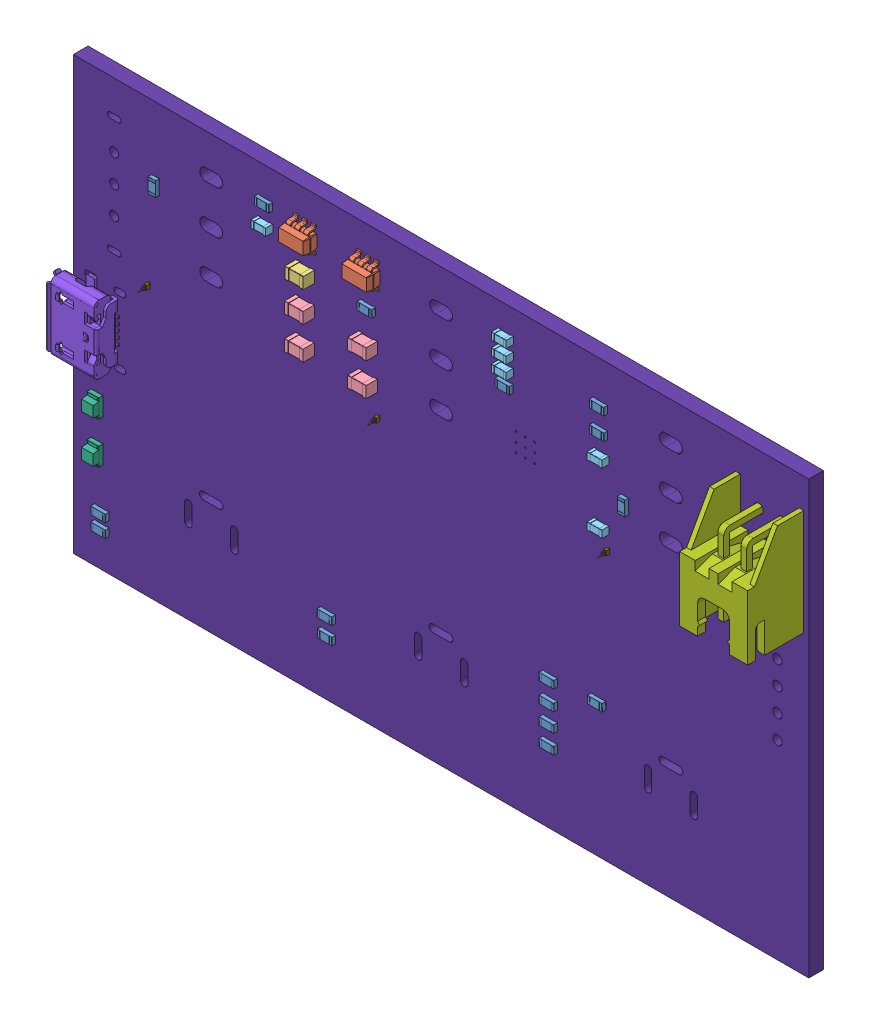
SolidWorks assembly ledTruck_PCB.step, configuration Default. Lengths in mm.
Overall size (80.38 47 12.68).
99 component instances, 19 part files, 0 mates.
Components (placement in the parent):
- ledTruck.step-1: ledTruck.step [Default] at origin size (80.38 47 12.68)
  - R_0603_1608Metric.step-1: R_0603_1608Metric.step [Default] at (162.2298 -104.8258 1.65) size (1.6 0.8 0.45)
    - SOLID.step-1: SOLID.step [Default] at origin size (1.6 0.8 0.45)
  - SOT-23-5.step-1: SOT-23-5.step [Default] at (130.302 -76.708 1.65) x (0 -1 0) z (0 0 1) size (2.8 2.9 1.55)
    - SOLID-0.step-1: SOLID-0.step [Default] at origin size (2.8 2.9 1.55)
  - SOT-23-5.step-2: SOT-23-5.step [Default] at (137.16 -76.708 1.65) x (0 -1 0) z (0 0 1) size (2.8 2.9 1.55)
    - SOLID-0.step-1: SOLID-0.step [Default] at origin size (2.8 2.9 1.55)
  - R_0603_1608Metric.step-2: R_0603_1608Metric.step [Default] at (162.433 -79.248 1.65) size (1.6 0.8 0.45)
    - SOLID.step-1: SOLID.step [Default] at origin size (1.6 0.8 0.45)
  - R_0603_1608Metric.step-3: R_0603_1608Metric.step [Default] at (162.433 -76.835 1.65) x (-1 0 0) z (0 0 1) size (1.6 0.8 0.45)
    - SOLID.step-1: SOLID.step [Default] at origin size (1.6 0.8 0.45)
  - R_0603_1608Metric.step-4: R_0603_1608Metric.step [Default] at (108.1929 -114.012 1.65) size (1.6 0.8 0.45)
    - SOLID.step-1: SOLID.step [Default] at origin size (1.6 0.8 0.45)
  - R_0603_1608Metric.step-5: R_0603_1608Metric.step [Default] at (108.1929 -115.512 1.65) size (1.6 0.8 0.45)
    - SOLID.step-1: SOLID.step [Default] at origin size (1.6 0.8 0.45)
  - R_0603_1608Metric.step-6: R_0603_1608Metric.step [Default] at (152.146 -80.01 1.65) size (1.6 0.8 0.45)
    - SOLID.step-1: SOLID.step [Default] at origin size (1.6 0.8 0.45)
  - R_0603_1608Metric.step-7: R_0603_1608Metric.step [Default] at (165.1 -84.836 1.65) x (0 1 0) z (0 0 1) size (1.6 0.8 0.45)
    - SOLID.step-1: SOLID.step [Default] at origin size (1.6 0.8 0.45)
  - R_0603_1608Metric.step-8: R_0603_1608Metric.step [Default] at (137.16 -80.264 1.65) x (-1 0 0) z (0 0 1) size (1.6 0.8 0.45)
    - SOLID.step-1: SOLID.step [Default] at origin size (1.6 0.8 0.45)
  - R_0603_1608Metric.step-9: R_0603_1608Metric.step [Default] at (156.972 -111.506 1.65) x (-1 0 0) z (0 0 1) size (1.6 0.8 0.45)
    - SOLID.step-1: SOLID.step [Default] at origin size (1.6 0.8 0.45)
  - R_0603_1608Metric.step-10: R_0603_1608Metric.step [Default] at (156.972 -107.442 1.65) size (1.6 0.8 0.45)
    - SOLID.step-1: SOLID.step [Default] at origin size (1.6 0.8 0.45)
  - R_0603_1608Metric.step-11: R_0603_1608Metric.step [Default] at (132.842 -113.284 1.65) size (1.6 0.8 0.45)
    - SOLID.step-1: SOLID.step [Default] at origin size (1.6 0.8 0.45)
  - R_0603_1608Metric.step-12: R_0603_1608Metric.step [Default] at (156.972 -109.474 1.65) x (-1 0 0) z (0 0 1) size (1.6 0.8 0.45)
    - SOLID.step-1: SOLID.step [Default] at origin size (1.6 0.8 0.45)
  - R_0603_1608Metric.step-13: R_0603_1608Metric.step [Default] at (156.972 -105.283 1.65) x (-1 0 0) z (0 0 1) size (1.6 0.8 0.45)
    - SOLID.step-1: SOLID.step [Default] at origin size (1.6 0.8 0.45)
  - R_0603_1608Metric.step-14: R_0603_1608Metric.step [Default] at (132.828 -111.379 1.65) size (1.6 0.8 0.45)
    - SOLID.step-1: SOLID.step [Default] at origin size (1.6 0.8 0.45)
  - L_0805_2012Metric.step-1: L_0805_2012Metric.step [Default] at (130.336 -80.264 1.65) x (-1 0 0) z (0 0 1) size (2 1.25 1.25)
    - SOLID-1.step-1: SOLID-1.step [Default] at origin size (2 1.25 1.25)
  - C_0805_2012Metric.step-1: C_0805_2012Metric.step [Default] at (130.302 -87.122 1.65) size (2 1.25 1.25)
    - SOLID-2.step-1: SOLID-2.step [Default] at origin size (2 1.25 1.25)
  - C_0603_1608Metric.step-1: C_0603_1608Metric.step [Default] at (152.146 -78.486 1.65) x (-1 0 0) z (0 0 1) size (1.6 0.8 0.8)
    - SOLID-3.step-1: SOLID-3.step [Default] at origin size (1.6 0.8 0.8)
  - C_0805_2012Metric.step-2: C_0805_2012Metric.step [Default] at (137.16 -83.566 1.65) size (2 1.25 1.25)
    - SOLID-2.step-1: SOLID-2.step [Default] at origin size (2 1.25 1.25)
  - C_0603_1608Metric.step-2: C_0603_1608Metric.step [Default] at (152.146 -76.962 1.65) x (-1 0 0) z (0 0 1) size (1.6 0.8 0.8)
    - SOLID-3.step-1: SOLID-3.step [Default] at origin size (1.6 0.8 0.8)
  - C_0603_1608Metric.step-3: C_0603_1608Metric.step [Default] at (152.146 -75.464 1.65) x (-1 0 0) z (0 0 1) size (1.6 0.8 0.8)
    - SOLID-3.step-1: SOLID-3.step [Default] at origin size (1.6 0.8 0.8)
  - C_0805_2012Metric.step-3: C_0805_2012Metric.step [Default] at (130.302 -83.566 1.65) size (2 1.25 1.25)
    - SOLID-2.step-1: SOLID-2.step [Default] at origin size (2 1.25 1.25)
  - C_0603_1608Metric.step-4: C_0603_1608Metric.step [Default] at (162.56 -81.534 1.65) size (1.6 0.8 0.8)
    - SOLID-3.step-1: SOLID-3.step [Default] at origin size (1.6 0.8 0.8)
  - C_0603_1608Metric.step-5: C_0603_1608Metric.step [Default] at (162.56 -88.138 1.65) size (1.6 0.8 0.8)
    - SOLID-3.step-1: SOLID-3.step [Default] at origin size (1.6 0.8 0.8)
  - C_0805_2012Metric.step-4: C_0805_2012Metric.step [Default] at (137.16 -87.122 1.65) size (2 1.25 1.25)
    - SOLID-2.step-1: SOLID-2.step [Default] at origin size (2 1.25 1.25)
  - R_0603_1608Metric.step-15: R_0603_1608Metric.step [Default] at (125.984 -75.946 1.65) size (1.6 0.8 0.45)
    - SOLID.step-1: SOLID.step [Default] at origin size (1.6 0.8 0.45)
  - R_0603_1608Metric.step-16: R_0603_1608Metric.step [Default] at (114.046 -80.264 1.65) x (0 -1 0) z (0 0 1) size (1.6 0.8 0.45)
    - SOLID.step-1: SOLID.step [Default] at origin size (1.6 0.8 0.45)
  - LED_0805_2012Metric.step-1: LED_0805_2012Metric.step [Default] at (107.6929 -108.512 1.65) x (0 -1 0) z (0 0 1) size (2 1.25 1.1)
    - SOLID-4.step-1: SOLID-4.step [Default] at origin size (2 1.25 1.1)
  - LED_0805_2012Metric.step-2: LED_0805_2012Metric.step [Default] at (107.6929 -103.962 1.65) x (0 -1 0) z (0 0 1) size (2 1.25 1.1)
    - SOLID-4.step-1: SOLID-4.step [Default] at origin size (2 1.25 1.1)
  - C_0603_1608Metric.step-6: C_0603_1608Metric.step [Default] at (125.984 -77.978 1.65) x (-1 0 0) z (0 0 1) size (1.6 0.8 0.8)
    - SOLID-3.step-1: SOLID-3.step [Default] at origin size (1.6 0.8 0.8)
  - SW_CuK_JS202011AQN_DPDT_Angled.step-1: SW_CuK_JS202011AQN_DPDT_Angled.step [Default] at (111.474 -79.012 1.65) x (0 -1 0) z (0 0 1) size (9 5.6 6.5) (hidden)
    - SOLID-5.step-1: SOLID-5.step [Default] at origin size (9 5.6 6.5)
  - JST_XH_S2B-XH-A_1x02_P2.50mm_Horizontal.step-1: JST_XH_S2B-XH-A_1x02_P2.50mm_Horizontal.step [Default] at (179.578 -78.012 1.65) size (7.4 11.5 9.5)
    - SOLID-6.step-1: SOLID-6.step [Default] at origin size (7.4 11.5 9.5)
  - USB_Micro-B_Molex_47346-0001.step-1: USB_Micro-B_Molex_47346-0001.step [Default] at (108.4213 -96.0044 1.65) x (0 -1 0) z (0 0 1) size (7.98 5.42 2.94)
    - SOLID-7.step-1: SOLID-7.step [Default] at origin size (7.98 5.42 2.94)
  - Crystal_SMD_0603-4Pin_6.0x3.5mm.step-1: Crystal_SMD_0603-4Pin_6.0x3.5mm.step [Default] at (162.56 -84.856 1.65) x (0 1 0) z (0 0 1) size (6 3.5 1.03)
    - SOLID-8.step-1: SOLID-8.step [Default] at origin size (6 3.5 1.03) (hidden)
  - 7101 ToggleSwitch.step-1: 7101 ToggleSwitch.step [Default] at (121.534 -82.012 10.15) size (0.36 0.5 1.28)
    - SOLID-9.step-1: SOLID-9.step [Default] at origin size (0.28 0.5 0.35)
    - SOLID-10.step-1: SOLID-10.step [Default] at origin size (0.24 0.24 0.35)
    - SOLID-11.step-1: SOLID-11.step [Default] at origin size (0.12 0.21 0.43)
    - SOLID-12.step-1: SOLID-12.step [Default] at origin size (0.36 0.31 0.06)
    - SOLID-13.step-1: SOLID-13.step [Default] at origin size (0.36 0.31 0.06)
    - SOLID-14.step-1: SOLID-14.step [Default] at origin size (0.08 0.03 0.16)
    - SOLID-15.step-1: SOLID-15.step [Default] at origin size (0.08 0.03 0.16)
    - SOLID-16.step-1: SOLID-16.step [Default] at origin size (0.08 0.03 0.16)
  - 7101 ToggleSwitch.step-2: 7101 ToggleSwitch.step [Default] at (146.534 -82.012 10.15) size (0.36 0.5 1.28)
    - SOLID-9.step-1: SOLID-9.step [Default] at origin size (0.28 0.5 0.35)
    - SOLID-10.step-1: SOLID-10.step [Default] at origin size (0.24 0.24 0.35)
    - SOLID-11.step-1: SOLID-11.step [Default] at origin size (0.12 0.21 0.43)
    - SOLID-12.step-1: SOLID-12.step [Default] at origin size (0.36 0.31 0.06)
    - SOLID-13.step-1: SOLID-13.step [Default] at origin size (0.36 0.31 0.06)
    - SOLID-14.step-1: SOLID-14.step [Default] at origin size (0.08 0.03 0.16)
    - SOLID-15.step-1: SOLID-15.step [Default] at origin size (0.08 0.03 0.16)
    - SOLID-16.step-1: SOLID-16.step [Default] at origin size (0.08 0.03 0.16)
  - 7101 ToggleSwitch.step-3: 7101 ToggleSwitch.step [Default] at (171.534 -82.012 10.15) size (0.36 0.5 1.28)
    - SOLID-9.step-1: SOLID-9.step [Default] at origin size (0.28 0.5 0.35)
    - SOLID-10.step-1: SOLID-10.step [Default] at origin size (0.24 0.24 0.35)
    - SOLID-11.step-1: SOLID-11.step [Default] at origin size (0.12 0.21 0.43)
    - SOLID-12.step-1: SOLID-12.step [Default] at origin size (0.36 0.31 0.06)
    - SOLID-13.step-1: SOLID-13.step [Default] at origin size (0.36 0.31 0.06)
    - SOLID-14.step-1: SOLID-14.step [Default] at origin size (0.08 0.03 0.16)
    - SOLID-15.step-1: SOLID-15.step [Default] at origin size (0.08 0.03 0.16)
    - SOLID-16.step-1: SOLID-16.step [Default] at origin size (0.08 0.03 0.16)
  - COMPOUND.step-1: COMPOUND.step [Default] at origin size (80 47 1.6)
